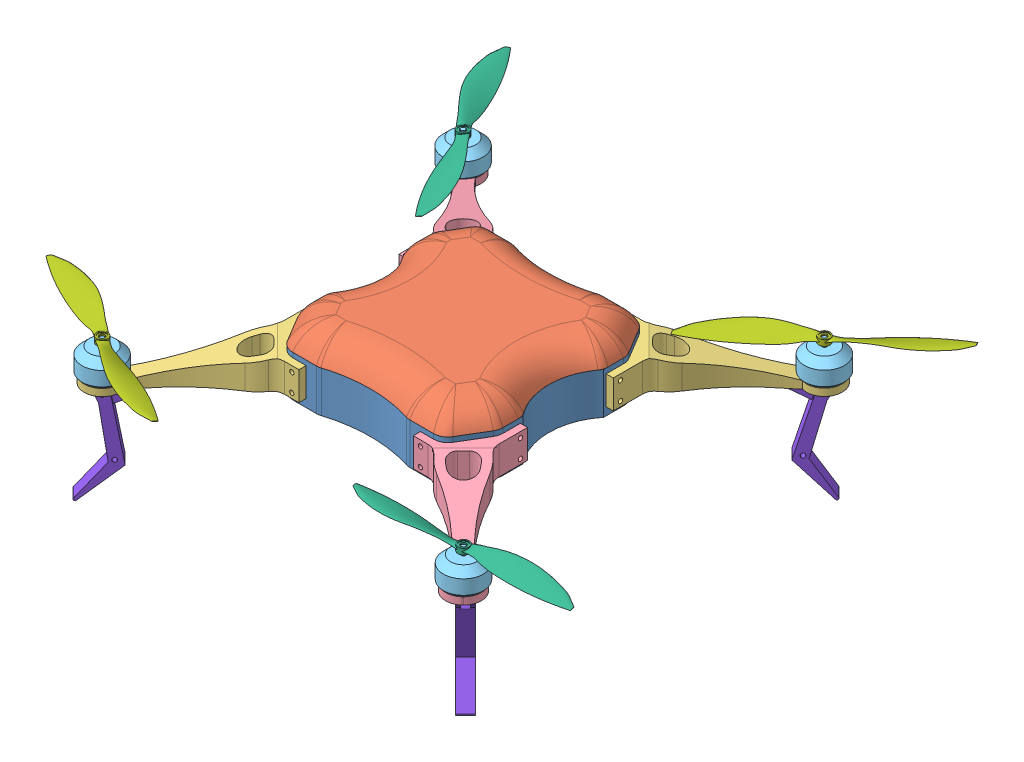
SolidWorks assembly Assem3, configuration Default. Lengths in mm.
Overall size (398.59 114.89 379.71).
18 component instances, 8 part files, 31 mates.
Components (placement in the parent):
- base3.2-1: base3.2 [Default] at (-52.2424 -33.4632 15.0425) size (140 29.45 140)
- kapak3-1: kapak3 [Default] at (1927.8091 1.5589 1103.0523) size (141.04 18.04 140.84)
- kanat3.1-1: kanat3.1 [Default] at (25.1243 -26.9632 -26.7908) x (0 0 -1) z (1 0 0) size (108.97 32.01 98.81)
- kanat3.1-2: kanat3.1 [Default] at (-121.209 -26.9632 98.8759) x (0 0 1) z (-1 0 0) size (108.97 32.01 98.81)
- kanat3.1-3-1: kanat3.1-3 [Default] at (14.791 -26.9632 109.2092) size (98.97 32 108.81)
- kanat3.1-3-2: kanat3.1-3 [Default] at (-110.8757 -26.9632 -37.1241) x (-1 0 0) z (0 0 -1) size (98.97 32 108.81)
- brushless-1: brushless [Default] at (78.2705 -21.9632 -90.4253) x (0.707107 0 -0.707107) z (0.707107 0 0.707107) size (28 22 28)
- brushless-2: brushless [Default] at (78.4255 -21.9632 162.3554) x (0.707107 0 0.707107) z (-0.707107 0 0.707107) size (28 22 28)
- brushless-3: brushless [Default] at (-174.3553 -21.9632 162.5104) x (0.707107 0 -0.707107) z (0.707107 0 0.707107) size (28 22 28)
- brushless-4: brushless [Default] at (-174.5102 -21.9632 -90.2704) x (0.707107 0 0.707107) z (-0.707107 0 0.707107) size (28 22 28)
- 6x3-counterclockwise-propeller-1: 6x3-counterclockwise-propeller [Default] at (-180.7792 -5.7379 -89.8962) x (0.758697 0 -0.651443) z (0.651443 0 0.758697) size (36.02 6.32 147.86)
- 6x3-counterclockwise-propeller-2: 6x3-counterclockwise-propeller [Default] at (75.8324 -4.4179 168.0752) x (-0.222366 0 -0.974963) z (0.974963 0 -0.222366) size (36.02 6.32 147.86)
- 6x3-clockwise-propeller-1: 6x3-clockwise-propeller [Default] at (-180.4076 -4.4206 164.1866) x (0.605771 0 -0.795639) z (0.795639 0 0.605771) size (36.02 6.32 147.86)
- 6x3-clockwise-propeller-2: 6x3-clockwise-propeller [Default] at (79.2131 -4.4206 -96.6343) x (0.478738 0 0.877958) z (-0.877958 0 0.478738) size (36.02 6.32 147.86)
- ayak1-1: ayak1 [Default] at (65.7981 -65.1136 155.385) x (0.707107 0 -0.707107) z (0.623288 -0.472254 0.623288) size (10 57 54.02)
- ayak1-2: ayak1 [Default] at (-163.4056 -65.9218 -84.8226) x (-0.707107 0 0.707107) z (-0.643138 -0.415628 -0.643138) size (10 57 54.02)
- ayak1-3: ayak1 [Default] at (-169.3299 -65.1189 151.8281) x (0.707107 0 0.707106) z (-0.648121 -0.399847 0.648122) size (10 57 54.02)
- ayak1-4: ayak1 [Default] at (70.5231 -63.6398 -77.021) x (-0.707107 0 -0.707106) z (0.611972 -0.500979 -0.611973) size (10 57 54.02)
Mates (geometry in assembly coordinates):
- Coincident8: coincident anti-aligned: circle of base3.2-1; circle of kanat3.1-3-1
- Coincident9: coincident anti-aligned: circle of base3.2-1; circle of kanat3.1-3-2
- Coincident10: coincident anti-aligned: circle of base3.2-1; circle of kanat3.1-3-2
- Coincident11: coincident anti-aligned: circle of base3.2-1; circle of kanat3.1-2
- Coincident12: coincident anti-aligned: circle of base3.2-1; circle of kanat3.1-1
- Concentric1: concentric anti-aligned: circle of kanat3.1-1; circle of brushless-1
- Concentric3: concentric anti-aligned: circle of kanat3.1-1; circle of brushless-1
- Coincident13: coincident anti-aligned: plane of kanat3.1-1 through (-0.5832 -21.9632 -186.956) normal (0 1 0); plane of brushless-1 through (78.2705 -21.9632 -90.4253) normal (0 -1 0)
- Concentric4: concentric anti-aligned: circle of kanat3.1-3-1; circle of brushless-2
- Concentric5: concentric anti-aligned: circle of kanat3.1-3-1; circle of brushless-2
- Coincident14: coincident anti-aligned: plane of kanat3.1-3-1 through (174.9561 -21.9632 83.5017) normal (0 1 0); plane of brushless-2 through (78.4255 -21.9632 162.3554) normal (0 -1 0)
- Concentric6: concentric anti-aligned: circle of kanat3.1-2; circle of brushless-3
- Concentric7: concentric anti-aligned: circle of kanat3.1-2; circle of brushless-3
- Coincident15: coincident anti-aligned: plane of kanat3.1-2 through (-95.5016 -21.9632 259.041) normal (0 1 0); plane of brushless-3 through (-174.3553 -21.9632 162.5104) normal (0 -1 0)
- Concentric8: concentric anti-aligned: circle of kanat3.1-3-2; circle of brushless-4
- Concentric9: concentric anti-aligned: circle of kanat3.1-3-2; circle of brushless-4
- Coincident16: coincident anti-aligned: plane of kanat3.1-3-2 through (-271.0409 -21.9632 -11.4167) normal (0 1 0); plane of brushless-4 through (-174.5102 -21.9632 -90.2704) normal (0 -1 0)
- Concentric10: concentric anti-aligned: circle of brushless-3; circle of 6x3-clockwise-propeller-1
- Coincident17: coincident anti-aligned: plane of brushless-3 through (-174.3553 0.0368 162.5104) normal (0 1 0); plane of 6x3-clockwise-propeller-1 through (-174.3553 0.0368 162.5104) normal (0 -1 0)
- Concentric11: concentric anti-aligned: circle of brushless-2; circle of 6x3-counterclockwise-propeller-2
- Coincident18: coincident anti-aligned: plane of brushless-2 through (78.4255 0.0368 162.3554) normal (0 1 0); plane of 6x3-counterclockwise-propeller-2 through (78.4255 0.0368 162.3554) normal (0 -1 0)
- Concentric12: concentric anti-aligned: circle of brushless-4; circle of 6x3-counterclockwise-propeller-1
- Coincident19: coincident aligned: plane of brushless-4 through (-174.5102 0.0368 -90.2704) normal (0 1 0); circle of 6x3-counterclockwise-propeller-1
- Concentric13: concentric anti-aligned: circle of brushless-1; circle of 6x3-clockwise-propeller-2
- Coincident20: coincident anti-aligned: plane of brushless-1 through (78.2705 0.0368 -90.4253) normal (0 1 0); plane of 6x3-clockwise-propeller-2 through (78.2705 0.0368 -90.4253) normal (0 -1 0)
- Coincident21: coincident anti-aligned: circle of base3.2-1; cylinder of kanat3.1-2 through (-93.0424 -5.9632 116.0425) axis (0 0 -1) radius 1.5
- Coincident23: coincident aligned: circle of kanat3.1-3-1; circle of ayak1-1
- Coincident24: coincident aligned: circle of kanat3.1-3-2; circle of ayak1-2
- Coincident26: coincident aligned: circle of kanat3.1-2; circle of ayak1-3
- Coincident27: coincident aligned: circle of kanat3.1-1; circle of ayak1-4
- Coincident28: coincident anti-aligned: circle of base3.2-1; cylinder of kanat3.1-1 through (-3.0424 -5.9632 -43.9575) axis (0 0 1) radius 1.5
